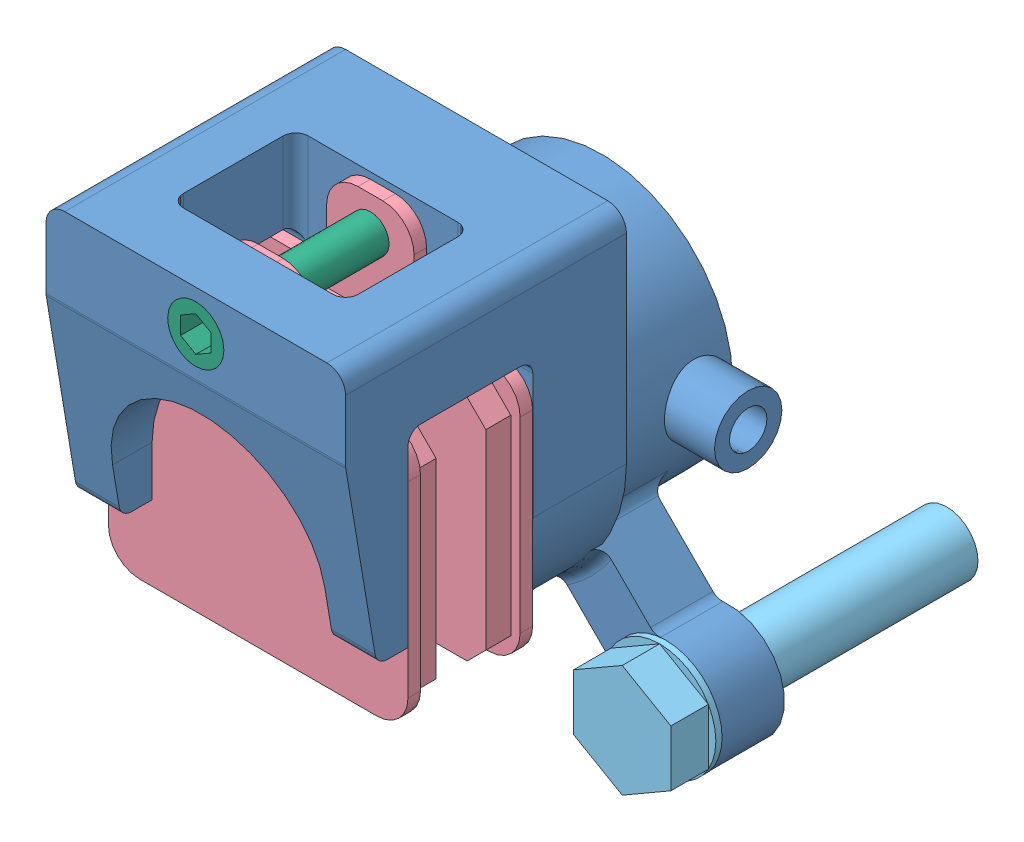
SolidWorks assembly caliper assembly, configuration Default. Lengths in mm.
Overall size (78.64 74.32 90).
8 component instances, 6 part files, 16 mates.
Components (placement in the parent):
- final caliper-1: final caliper [Default] at (41.8204 -6.3717 85.9954) size (78.64 74.32 65)
- seal-2: seal [Default] at (41.8204 61.1283 91.9954) x (0.978524 0.206135 0) z (0 0 1) size (38 38 4)
- piston-1: piston [Default] at (41.8204 61.1283 75.9954) size (33.9 33.9 28)
- brake pad-1: brake pad [Default] at (41.8204 61.1283 101.0283) size (48 54 6)
- brake pad-2: brake pad [Default] at (41.8204 61.1283 120.9954) x (-1 0 0) z (0 0 -1) size (48 54 6)
- floating pin-1: floating pin [Default] at (72.1407 30.808 86.9954) size (18 18 52)
- floating pin-2: floating pin [Default] at (11.5001 30.808 86.9954) size (18 18 52)
- pad pin-1: pad pin [Default] at (41.8204 89.6283 126.9954) size (9 9 40)
Mates (geometry in assembly coordinates):
- Concentric1: concentric anti-aligned: cylinder of final caliper-1 through (41.8204 61.1283 91.9954) axis (0 0 1) radius 19; cylinder of seal-2 through (41.8204 61.1283 95.9954) axis (0 0 -1) radius 19
- Coincident2: coincident aligned: axis of final caliper-1 through (41.8204 61.1283 133.3993) axis (0 0 -1); axis of seal-2 through (41.8204 61.1283 95.9954) axis (0 0 -1)
- Coincident3: coincident anti-aligned: plane of final caliper-1 through (41.8204 61.1283 91.9954) normal (0 0 1); plane of seal-2 through (41.8204 61.1283 91.9954) normal (0 0 -1)
- Coincident4: coincident anti-aligned: axis of final caliper-1 through (41.8204 61.1283 91.9954) axis (0 0 1); axis of piston-1 through (41.8204 61.1283 100.9954) axis (0 0 -1)
- Coincident5: coincident anti-aligned: plane of final caliper-1 through (41.8204 61.1283 72.9954) normal (0 0 1); plane of piston-1 through (41.8204 61.1283 72.9954) normal (0 0 -1)
- Coincident6: coincident anti-aligned: axis of final caliper-1 through (41.8204 89.6283 90.9954) axis (0 0 1); axis of brake pad-1 through (41.8204 89.6283 103.0283) axis (0 0 -1)
- Coincident8: coincident anti-aligned: plane of final caliper-1 through (17.8204 53.1283 120.9954) normal (0 0 -1); plane of brake pad-2 through (39.8204 90.1283 120.9954) normal (0 0 1)
- Parallel2: parallel aligned: plane of final caliper-1 through (20.8204 96.1283 100.9954) normal (0 1 0); plane of brake pad-2 through (42.3204 78.6283 114.9954) normal (0 1 0)
- Coincident12: coincident aligned: axis of final caliper-1 through (41.8204 89.6283 120.9954) axis (0 0 1); axis of brake pad-2 through (41.8204 89.6283 118.9954) axis (0 0 1)
- Coincident13: coincident aligned: plane of final caliper-1 through (20.8204 93.1283 130.9954) normal (0 0 1); plane of pad pin-1 through (41.8204 89.6283 130.9954) normal (0 0 1)
- Coincident14: coincident aligned: axis of final caliper-1 through (41.8204 89.6283 124.9954) axis (0 0 1); axis of pad pin-1 through (41.8204 89.6283 90.9954) axis (0 0 1)
- Coincident15: coincident aligned: axis of final caliper-1 through (72.1407 30.808 75.9954) axis (0 0 1); axis of floating pin-1 through (72.1407 30.808 40.9954) axis (0 0 1)
- Coincident16: coincident anti-aligned: plane of final caliper-1 through (41.8204 61.1283 85.9954) normal (0 0 1); plane of floating pin-1 through (72.1407 30.808 85.9954) normal (0 0 -1)
- Coincident17: coincident aligned: axis of final caliper-1 through (11.5001 30.808 75.9954) axis (0 0 1); axis of floating pin-2 through (11.5001 30.808 40.9954) axis (0 0 1)
- Coincident18: coincident anti-aligned: plane of final caliper-1 through (41.8204 61.1283 85.9954) normal (0 0 1); plane of floating pin-2 through (11.5001 30.808 85.9954) normal (0 0 -1)
- Parallel3: parallel aligned: plane of final caliper-1 through (65.8204 93.1283 100.9954) normal (1 0 0); plane of brake pad-1 through (64.3204 43.6283 107.0283) normal (1 0 0)
